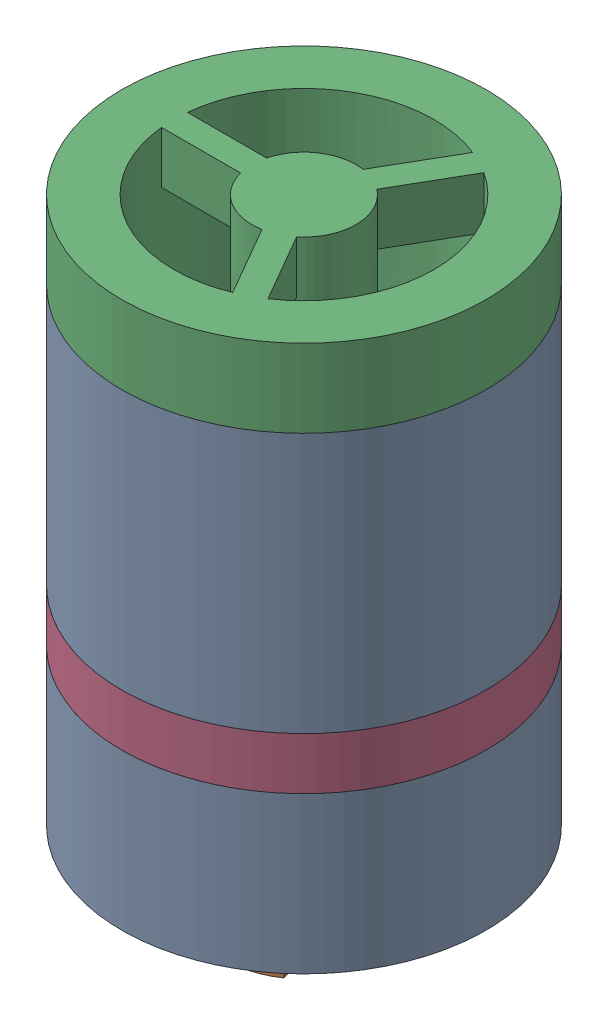
SolidWorks assembly Check valve, configuration 默认. Lengths in mm.
Overall size (14 24 14).
4 component instances, 4 part files, 0 mates.
Components (placement in the parent):
- Check valve housing-1: Check valve housing [默认] at origin size (14 18 14)
- Valve-1: Valve [默认] at (0 5 0) x (0.259222 0 0.965818) z (0.965818 0 -0.259222) size (8 11 8)
- Valve lock-1: Valve lock [默认] at (0 13 0) size (14 8 14)
- Seal-1: Seal [默认] at (0 6 0) size (14 2 14)
